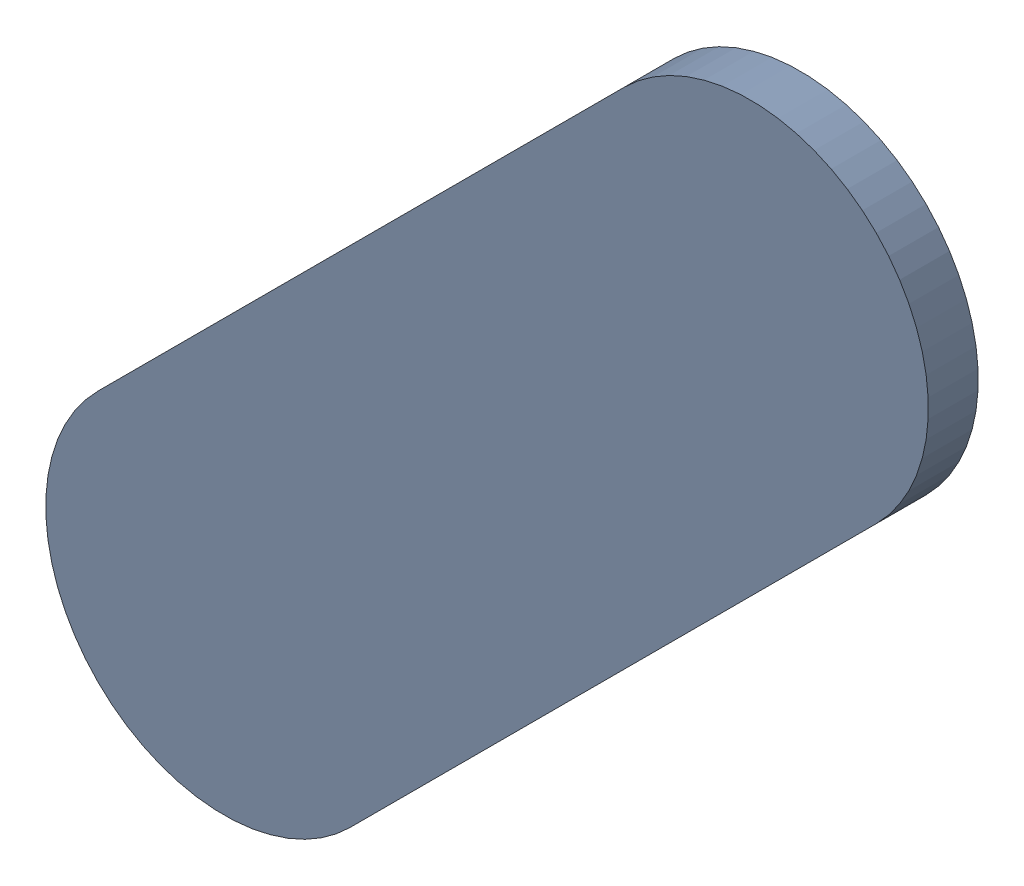
SolidWorks assembly Track (22.1mm,28.1mm)(22.475mm,28.475mm) on Top Layer, configuration Predeterminado. Lengths in mm.
Overall size (0.63 0.63 0.04).
2 component instances, 1 part files, 0 mates.
Components (placement in the parent):
- Track (22.1mm,28.1mm)(22.475mm,28.475mm) on Top Layer-1-1: Track (22.1mm,28.1mm)(22.475mm,28.475mm) on Top Layer-1 [Predeterminado] at (-68.317 -44.187 -0.0457) size (0.63 0.63 0.04)
  - Track (22.1mm,28.1mm)(22.475mm,28.475mm) on Top Layer-Part-1-1: Track (22.1mm,28.1mm)(22.475mm,28.475mm) on Top Layer-Part-1 [Predeterminado] at origin size (0.63 0.63 0.04)
